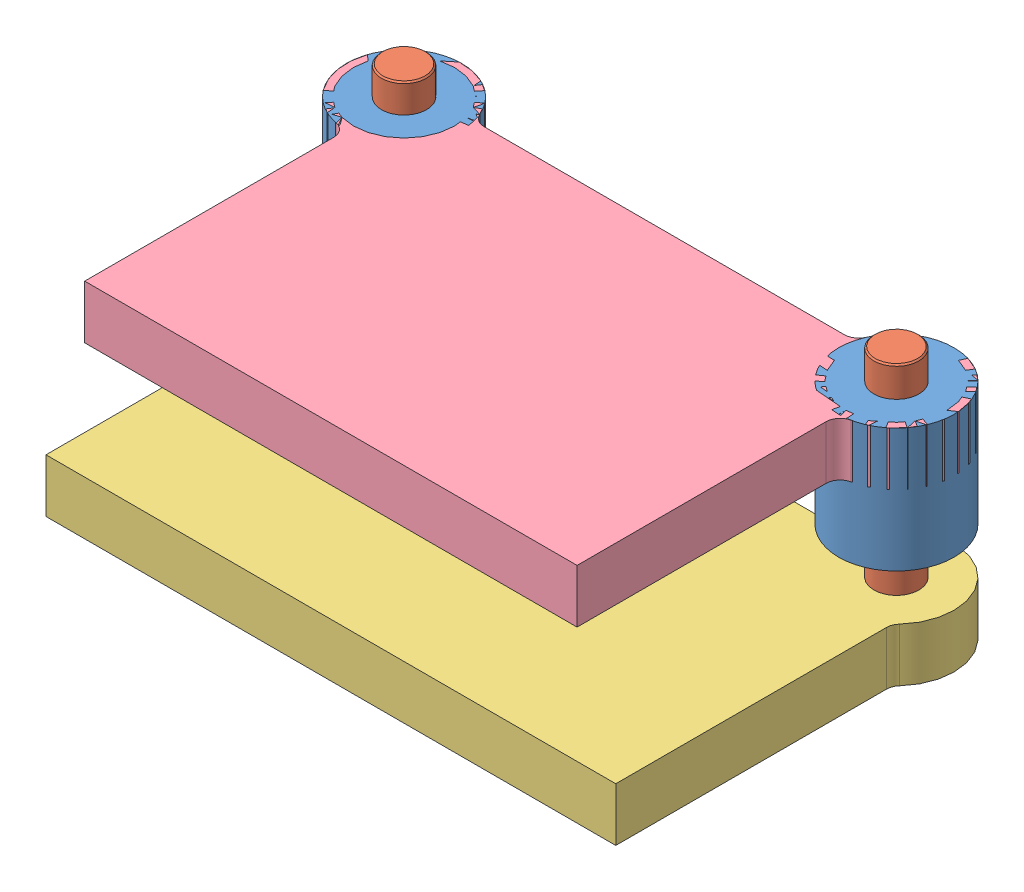
SolidWorks assembly Assem5, configuration Default. Lengths in mm.
Overall size (432 181 268).
6 component instances, 4 part files, 10 mates.
Components (placement in the parent):
- boosh-1: boosh [Default] at (-75.2286 74.2152 145.144) size (82 88 82)
- boosh-2: boosh [Default] at (-425.2286 74.2152 145.144) size (82 88 82)
- mile-1: mile [Default] at (-75.2286 3.5546 145.144) size (32 180 32)
- mile-2: mile [Default] at (-425.2286 2.5546 145.144) size (32 180 32)
- kafsake paiini-1: kafsake paiini [Default] at (-250.2286 3.5546 372.144) size (432 38 268)
- kafsake balaii-1: kafsake balaii [Default] at (-250.2286 124.2152 372.144) size (432 38 268)
Mates (geometry in assembly coordinates):
- Concentric1: concentric aligned: cylinder of boosh-1 through (-75.2286 162.2152 145.144) axis (0 -1 0) radius 41; cylinder of kafsake balaii-1 through (-75.2286 162.2152 145.144) axis (0 -1 0) radius 36
- Coincident1: coincident aligned: plane of boosh-1 through (-75.2286 162.2152 145.144) normal (0 1 0); plane of kafsake balaii-1 through (-425.2286 162.2152 145.144) normal (0 1 0)
- Concentric2: concentric aligned: cylinder of boosh-2 through (-425.2286 162.2152 145.144) axis (0 -1 0) radius 41; cylinder of kafsake balaii-1 through (-425.2286 162.2152 145.144) axis (0 -1 0) radius 36
- Coincident2: coincident aligned: plane of boosh-2 through (-425.2286 162.2152 145.144) normal (0 1 0); plane of kafsake balaii-1 through (-425.2286 162.2152 145.144) normal (0 1 0)
- Concentric3: concentric aligned: cylinder of mile-1 through (-75.2286 183.5546 145.144) axis (0 -1 0) radius 16; cylinder of kafsake paiini-1 through (-75.2286 41.5546 145.144) axis (0 -1 0) radius 16
- Coincident3: coincident aligned: plane of mile-1 through (-75.2286 3.5546 145.144) normal (0 -1 0); plane of kafsake paiini-1 through (-425.2286 3.5546 145.144) normal (0 -1 0)
- Concentric4: concentric aligned: cylinder of mile-2 through (-425.2286 182.5546 145.144) axis (0 -1 0) radius 16; cylinder of kafsake paiini-1 through (-425.2286 41.5546 145.144) axis (0 -1 0) radius 16
- Coincident4: coincident anti-aligned: circle of mile-2; plane of kafsake paiini-1 through (-425.2286 3.5546 145.144) normal (0 -1 0)
- Concentric5: concentric aligned: cylinder of boosh-1 through (-75.2286 162.2152 145.144) axis (0 -1 0) radius 16; cylinder of mile-1 through (-75.2286 183.5546 145.144) axis (0 -1 0) radius 16
- Concentric6: concentric aligned: cylinder of boosh-2 through (-425.2286 162.2152 145.144) axis (0 -1 0) radius 16; cylinder of mile-2 through (-425.2286 182.5546 145.144) axis (0 -1 0) radius 16
